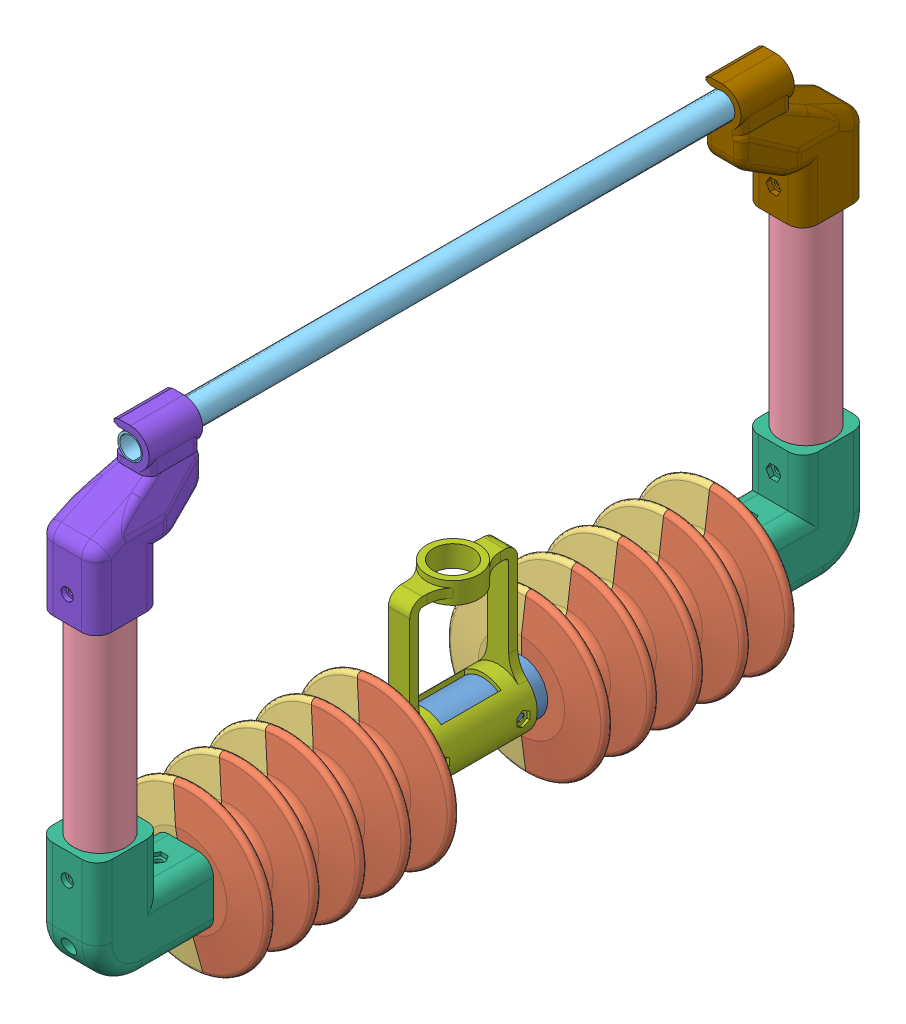
SolidWorks assembly Assembly FCO Detector, configuration Default. Lengths in mm.
Overall size (86.82 240.31 363.33).
13 component instances, 9 part files, 32 mates.
Components (placement in the parent):
- frame isolator-1: frame isolator [Default] at (131.0408 231.6785 169.1817) size (24.7 24.7 300)
- isolator atas-3: isolator atas [Default] at (131.0408 231.6785 240.1817) x (1 0 0) z (0 -1 0) size (36.95 94 73.9)
- isolator bawah-1: isolator bawah [Default] at (131.0408 231.6785 240.1817) x (-1 0 0) z (0 1 0) size (36.95 94 73.9)
- isolator atas-4: isolator atas [Default] at (131.0408 231.6785 398.1817) x (0.981044 0.193785 0) z (0.193785 -0.981044 0) size (36.95 94 73.9)
- isolator bawah-2: isolator bawah [Default] at (131.0408 231.6785 398.1817) x (-0.981044 -0.193785 0) z (-0.193785 0.981044 0) size (36.95 94 73.9)
- frame sambungam-1: frame sambungam [Default] at (131.0408 246.9785 484.4817) x (0.40534 0 -0.914166) z (0 1 0) size (24.7 24.7 140)
- frame sambungam-2: frame sambungam [Default] at (131.0408 386.9785 153.8817) x (-0.904918 0 0.425586) z (0 -1 0) size (24.7 24.7 140)
- fuse-1: fuse [Default] at (131.0408 419.7785 168.1817) x (0.735904 -0.677086 0) z (0 0 1) size (11.9 11.9 302)
- terminal-1: terminal [Default] at (131.0408 263.9785 484.4817) x (0 0 1) z (0 1 0) size (54.6 27.8 54.6)
- terminal-2: terminal [Default] at (131.0408 263.9785 153.8817) x (0 0 -1) z (0 1 0) size (54.6 27.8 54.6)
- mount sensor-1: mount sensor [Default] at (131.0408 298.7785 319.1817) x (0 0 -1) z (0 -1 0) size (50.55 28.4 81.3)
- terminal fuse atas 2-1: terminal fuse atas 2 [Default] at (131.0408 369.9785 385.8817) x (0 0 -1) z (0 -1 0) size (54.6 27.4 65.6)
- terminal fuse atas-1: terminal fuse atas [Default] at (131.0408 369.9785 153.8817) x (0 0 -1) z (0 -1 0) size (54.6 27.4 65.6)
Mates (geometry in assembly coordinates):
- Coincident10: coincident aligned: plane of isolator atas-3 through (131.0408 231.6785 193.1817) normal (0 0 -1); plane of isolator bawah-1 through (131.0408 231.6785 193.1817) normal (0 0 -1)
- Coincident16: coincident aligned: plane of isolator atas-4 through (131.0408 231.6785 351.1817) normal (0 0 -1); plane of isolator bawah-2 through (131.0408 231.6785 351.1817) normal (0 0 -1)
- Concentric12: concentric anti-aligned: cylinder of frame isolator-1 through (131.0408 231.6785 469.1817) axis (0 0 -1) radius 12.35; cylinder of isolator atas-4 through (131.0408 231.6785 445.1817) axis (0 0 1) radius 11.2
- Concentric13: concentric anti-aligned: cylinder of frame isolator-1 through (131.0408 231.6785 469.1817) axis (0 0 -1) radius 12.35; cylinder of isolator bawah-1 through (131.0408 231.6785 287.1817) axis (0 0 1) radius 11.2
- Concentric14: concentric anti-aligned: cylinder of frame isolator-1 through (131.0408 231.6785 469.1817) axis (0 0 -1) radius 12.35; cylinder of isolator atas-3 through (131.0408 231.6785 287.1817) axis (0 0 1) radius 11.2
- Concentric15: concentric anti-aligned: cylinder of frame isolator-1 through (131.0408 231.6785 469.1817) axis (0 0 -1) radius 12.35; cylinder of isolator bawah-2 through (131.0408 231.6785 445.1817) axis (0 0 1) radius 11.2
- Concentric16: concentric anti-aligned: cylinder of frame isolator-1 through (131.0408 231.6785 469.1817) axis (0 0 -1) radius 12.35; cylinder of terminal-1 through (131.0408 231.6785 445.1817) axis (0 0 1) radius 11.2
- Concentric17: concentric aligned: cylinder of frame sambungam-1 through (131.0408 386.9785 484.4817) axis (0 -1 0) radius 12.35; cylinder of terminal-1 through (131.0408 270.9785 484.4817) axis (0 -1 0) radius 11.2
- Coincident17: coincident anti-aligned: plane of frame isolator-1 through (131.0408 231.6785 469.1817) normal (0 0 1); plane of terminal-1 through (144.9408 246.9785 469.1817) normal (0 0 -1)
- Parallel1: parallel anti-aligned: plane of terminal-1 through (117.1408 246.9785 469.1817) normal (-1 0 0)
- Coincident19: coincident anti-aligned: plane of frame sambungam-1 through (131.0408 246.9785 484.4817) normal (0 -1 0); plane of terminal-1 through (73.8659 246.9785 469.1817) normal (0 1 0)
- Concentric18: concentric aligned: cylinder of frame isolator-1 through (131.0408 231.6785 469.1817) axis (0 0 -1) radius 12.35; cylinder of terminal-2 through (131.0408 231.6785 193.1817) axis (0 0 -1) radius 11.2
- Coincident20: coincident anti-aligned: plane of frame isolator-1 through (131.0408 231.6785 169.1817) normal (0 0 -1); plane of terminal-2 through (117.1408 246.9785 169.1817) normal (0 0 1)
- Coincident21: coincident aligned: plane of terminal-1 through (117.1408 246.9785 469.1817) normal (-1 0 0); plane of terminal-2 through (117.1408 246.9785 169.1817) normal (-1 0 0)
- Concentric19: concentric anti-aligned: cylinder of frame sambungam-2 through (131.0408 246.9785 153.8817) axis (0 1 0) radius 12.35; cylinder of terminal-2 through (131.0408 270.9785 153.8817) axis (0 -1 0) radius 11.2
- Coincident22: coincident anti-aligned: plane of frame sambungam-2 through (131.0408 246.9785 153.8817) normal (0 -1 0); plane of terminal-2 through (188.2158 246.9785 169.1817) normal (0 1 0)
- Concentric23: concentric anti-aligned: cylinder of frame isolator-1 through (131.0408 231.6785 469.1817) axis (0 0 -1) radius 12.35; cylinder of mount sensor-1 through (131.0408 231.6785 253.7445) axis (0 0 1) radius 11.2
- Parallel2: parallel aligned: plane of terminal-2 through (117.1408 246.9785 169.1817) normal (-1 0 0); plane of mount sensor-1 through (126.0408 295.8785 319.1817) normal (-1 0 0)
- Width1: width aligned: plane of mount sensor-1 through (136.0408 242.8785 344.4552) normal (0 0 1); plane of isolator atas-3 through (136.0408 242.8785 293.9082) normal (0 0 -1); plane of mount sensor-1 through (131.0408 231.6785 287.1817) normal (0 0 1); plane of isolator atas-4 through (131.0408 231.6785 351.1817) normal (0 0 -1)
- Parallel3: parallel anti-aligned: plane of isolator bawah-1 through (131.0408 176.5439 414.4587) normal (1 0 0); plane of terminal-2 through (117.1408 246.9785 169.1817) normal (-1 0 0)
- Coincident29: coincident anti-aligned: plane of isolator atas-3 through (131.0408 286.8132 414.4587) normal (-1 0 0); plane of isolator bawah-1 through (131.0408 176.5439 414.4587) normal (1 0 0)
- Coincident30: coincident anti-aligned: plane of isolator bawah-1 through (131.0408 231.6785 193.1817) normal (0 0 -1); plane of terminal-2 through (131.0408 263.9785 193.1817) normal (0 0 1)
- Coincident31: coincident anti-aligned: plane of isolator atas-4 through (120.3566 285.768 572.4587) normal (-0.981044 -0.193785 0); plane of isolator bawah-2 through (141.7251 177.589 572.4587) normal (0.981044 0.193785 0)
- Coincident32: coincident anti-aligned: plane of isolator bawah-2 through (131.0408 231.6785 445.1817) normal (0 0 1); plane of terminal-1 through (131.0408 263.9785 445.1817) normal (0 0 -1)
- Concentric24: concentric anti-aligned: cylinder of frame sambungam-1 through (131.0408 386.9785 484.4817) axis (0 -1 0) radius 12.35; cylinder of terminal fuse atas 2-1 through (131.0408 362.9785 484.4817) axis (0 1 0) radius 11.2
- Parallel4: parallel aligned: plane of terminal-1 through (144.9408 246.9785 469.1817) normal (1 0 0); plane of terminal fuse atas 2-1 through (144.7408 386.9785 469.1817) normal (1 0 0)
- Coincident34: coincident anti-aligned: circle of frame sambungam-1; plane of terminal fuse atas 2-1 through (71.895 386.9785 469.1817) normal (0 -1 0)
- Concentric25: concentric aligned: cylinder of frame sambungam-2 through (131.0408 246.9785 153.8817) axis (0 1 0) radius 12.35; cylinder of terminal fuse atas-1 through (131.0408 362.9785 153.8817) axis (0 1 0) radius 11.2
- Coincident35: coincident aligned: plane of terminal fuse atas 2-1 through (131.0408 362.9785 484.4817) normal (0 -1 0); plane of terminal fuse atas-1 through (131.0408 362.9785 153.8817) normal (0 -1 0)
- Parallel5: parallel aligned: plane of terminal-2 through (144.9408 246.9785 169.1817) normal (1 0 0); plane of terminal fuse atas-1 through (144.7408 386.9785 169.1817) normal (1 0 0)
- Concentric26: concentric anti-aligned: cylinder of fuse-1 through (131.0408 419.7785 470.1817) axis (0 0 -1) radius 5.95; cylinder of terminal fuse atas-1 through (131.0408 419.7785 168.1817) axis (0 0 1) radius 5.6
- Coincident37: coincident aligned: plane of fuse-1 through (131.0408 419.7785 470.1817) normal (0 0 1); plane of terminal fuse atas 2-1 through (131.0408 369.9785 470.1817) normal (0 0 1)
